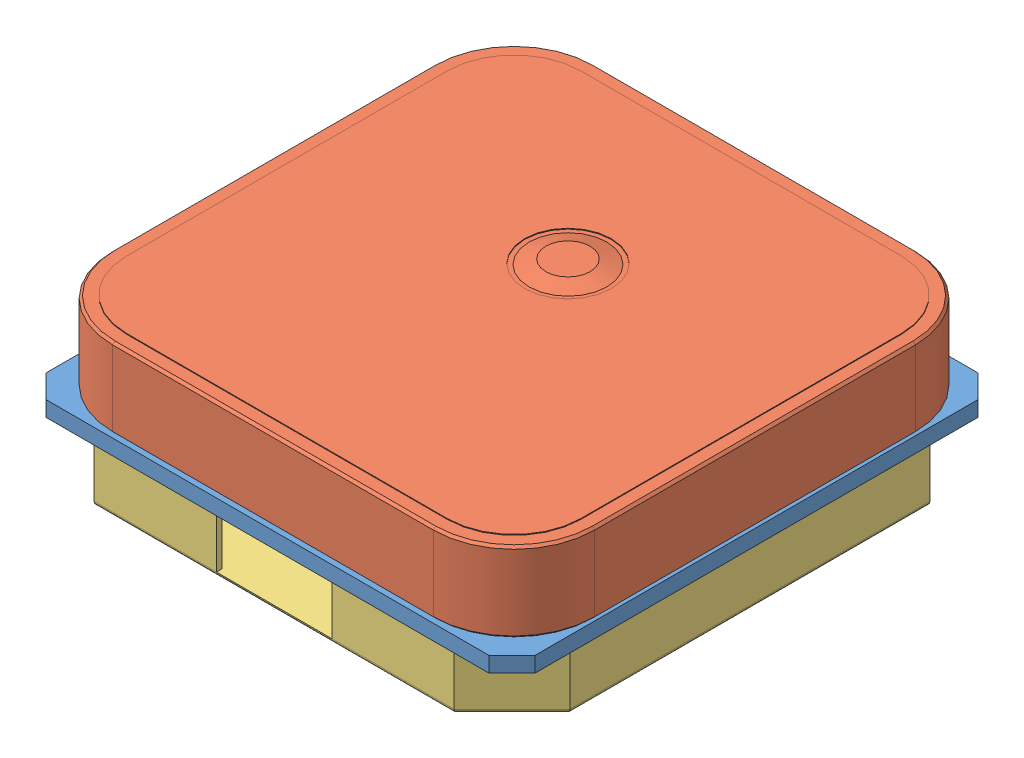
SolidWorks assembly Assemblage1, configuration Défaut. Lengths in mm.
Overall size (25.4 8.27 25.4).
3 component instances, 3 part files, 5 mates.
Components (placement in the parent):
- GPS_board-1: GPS_board [Défaut] at (-12.3952 2.0513 25.4) size (25.4 0.8 25.4)
- GPS_ant-1: GPS_ant [Défaut] at (-12.0993 2.8513 25.23) size (25.04 4.39 25.04)
- GPS_back-1: GPS_back [Défaut] at (-12.0452 2.0513 0.35) x (1 0 0) z (0 0 -1) size (24.7 3.08 24.7)
Mates (geometry in assembly coordinates):
- Coïncidente1: coincident anti-aligned: plane of GPS_board-1 through (-12.3952 2.8513 25.4) normal (0 1 0); plane of GPS_ant-1 through (-12.0993 2.8513 25.23) normal (0 -1 0)
- Distance1: distance = 0.19 mm aligned: plane of GPS_ant-1 through (-12.0993 6.9913 0.19) normal (0 0 -1); plane of GPS_board-1 through (-12.3952 2.8513 0) normal (0 0 -1)
- Coïncidente3: coincident: plane of GPS_board-1 through (-12.3952 2.0513 25.4) normal (0 -1 0); plane of GPS_back-1 through (-29.7248 2.0513 0.35) normal (0 1 0)
- Distance3: distance = 0.35 mm: plane of GPS_board-1 through (-12.3952 2.8513 25.4) normal (0 0 1); plane of GPS_back-1 through (-12.0452 -1.0287 25.05) normal (0 0 1)
- Distance4: distance = 0.35 mm aligned: plane of GPS_back-1 through (12.6548 -1.0287 0.35) normal (1 0 0); plane of GPS_board-1 through (13.0048 2.8513 25.4) normal (1 0 0)
